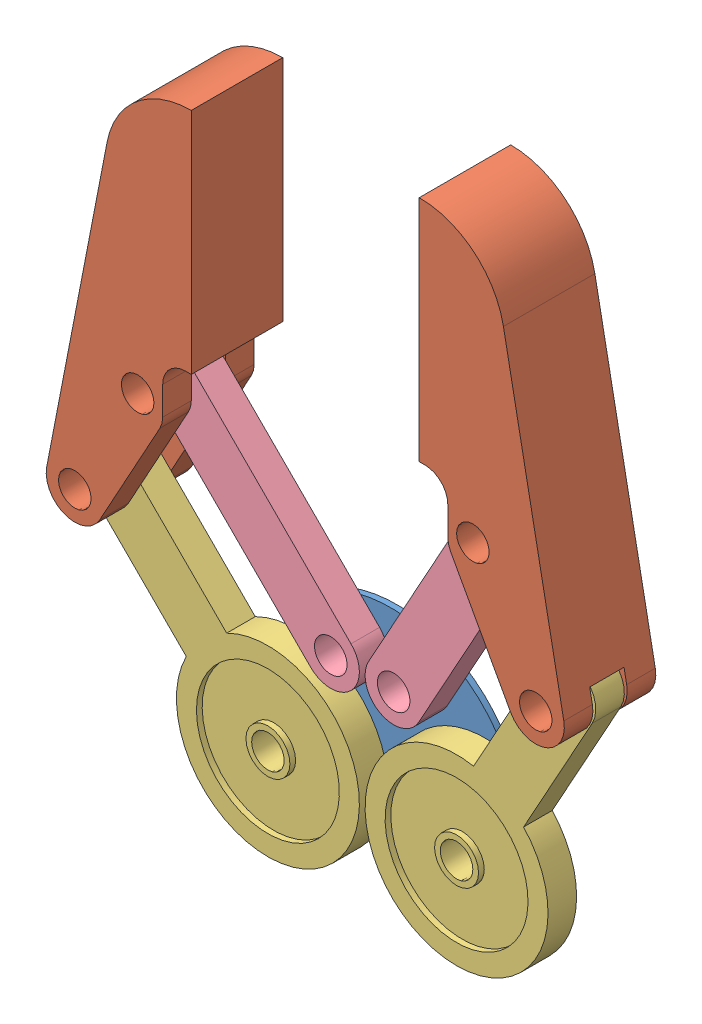
SolidWorks assembly Claw_1, configuration Default. Lengths in mm.
Overall size (111.91 125.22 16).
7 component instances, 4 part files, 18 mates.
Components (placement in the parent):
- Arm_Plate-1: Arm_Plate [Default] at (16.3184 9.8304 30.4902) x (0 -1 0) z (0 0 1) size (32.5 45 1)
- Grip-1: Grip [Default] at (31.79 112.4275 25.9902) x (0 -1 0) z (0 0 1) size (72.59 25.38 16)
- Arm_Gear-1: Arm_Gear [Default] at (-14.3238 23.9725 33.9902) x (0.707107 -0.707107 0) z (0 0 1) size (61 32 5)
- Arm_Link-1: Arm_Link [Default] at (31.4948 47.3338 33.9902) x (-0.483819 -0.875168 0) z (0 0 -1) size (50 10 5)
- Arm_Link-2: Arm_Link [Default] at (-3.3238 43.9725 33.9902) x (0.707107 -0.707107 0) z (0 0 -1) size (50 10 5)
- Arm_Gear-2: Arm_Gear [Default] at (42.4948 27.3338 33.9902) x (-0.483819 -0.875168 0) z (0 0 1) size (61 32 5)
- Grip-2: Grip [Default] at (-8.0848 105.7051 41.9902) x (0 -1 0) z (0 0 -1) size (72.59 25.38 16)
Mates (geometry in assembly coordinates):
- Coincident2: coincident anti-aligned: plane of Arm_Plate-1 through (16.3184 14.8304 31.4902) normal (0 0 1); plane of Arm_Gear-1 through (-4.0627 49.6417 31.4902) normal (0 0 -1)
- Concentric1: concentric aligned: cylinder of Arm_Plate-1 through (-0.1816 9.8304 31.4902) axis (0 0 -1) radius 2.85; cylinder of Arm_Gear-1 through (-0.1816 9.8304 36.4902) axis (0 0 -1) radius 2.85
- Concentric2: concentric aligned: cylinder of Arm_Plate-1 through (32.8184 9.8304 31.4902) axis (0 0 -1) radius 2.85; cylinder of Arm_Gear-2 through (32.8184 9.8304 36.4902) axis (0 0 -1) radius 2.85
- Coincident3: coincident anti-aligned: plane of Arm_Plate-1 through (16.3184 14.8304 31.4902) normal (0 0 1); plane of Arm_Gear-2 through (36.6995 49.6417 31.4902) normal (0 0 -1)
- Concentric3: concentric anti-aligned: cylinder of Arm_Gear-1 through (-4.0627 49.6417 36.4902) axis (0 0 -1) radius 2.85; cylinder of Grip-2 through (-4.0627 49.6417 36.9902) axis (0 0 1) radius 2.85
- Concentric4: concentric aligned: cylinder of Grip-1 through (36.6995 49.6417 41.9902) axis (0 0 -1) radius 2.85; cylinder of Arm_Gear-2 through (36.6995 49.6417 36.4902) axis (0 0 -1) radius 2.85
- Width1: width anti-aligned: plane of Grip-1 through (79.1256 44.6417 36.9902) normal (0 0 -1); plane of Arm_Gear-2 through (17.3184 73.2321 30.9902) normal (0 0 1); plane of Grip-1 through (36.6995 49.6417 36.4902) normal (0 0 1); plane of Arm_Gear-2 through (36.6995 49.6417 31.4902) normal (0 0 -1)
- Width2: width anti-aligned: plane of Grip-2 through (-46.4889 44.6417 30.9902) normal (0 0 1); plane of Arm_Gear-1 through (15.3184 73.2321 36.9902) normal (0 0 -1); plane of Grip-2 through (-4.0627 49.6417 31.4902) normal (0 0 -1); plane of Arm_Gear-1 through (-4.0627 49.6417 36.4902) normal (0 0 1)
- Concentric5: concentric anti-aligned: cylinder of Arm_Plate-1 through (21.8184 29.8304 31.4902) axis (0 0 -1) radius 2.85; cylinder of Arm_Link-1 through (21.8184 29.8304 31.4902) axis (0 0 1) radius 2.85
- Coincident4: coincident anti-aligned: plane of Grip-1 through (32.0426 112.2867 41.9902) normal (-1 0 0); plane of Grip-2 through (-8.0848 105.7051 25.9902) normal (1 0 0)
- Concentric6: concentric anti-aligned: cylinder of Grip-1 through (25.6995 69.6417 41.9902) axis (0 0 -1) radius 2.85; cylinder of Arm_Link-1 through (25.6995 69.6417 31.4902) axis (0 0 1) radius 2.85
- Concentric7: concentric anti-aligned: cylinder of Arm_Plate-1 through (10.8184 29.8304 31.4902) axis (0 0 -1) radius 2.85; cylinder of Arm_Link-2 through (10.8184 29.8304 31.4902) axis (0 0 1) radius 2.85
- Concentric8: concentric aligned: cylinder of Arm_Link-2 through (6.9373 69.6417 31.4902) axis (0 0 1) radius 2.85; cylinder of Grip-2 through (6.9373 69.6417 36.9902) axis (0 0 1) radius 2.85
- Coincident5: coincident anti-aligned: plane of Arm_Plate-1 through (16.3184 14.8304 31.4902) normal (0 0 1); plane of Arm_Link-1 through (25.6995 69.6417 31.4902) normal (0 0 -1)
- Coincident6: coincident anti-aligned: plane of Arm_Plate-1 through (16.3184 14.8304 31.4902) normal (0 0 1); plane of Arm_Link-2 through (6.9373 69.6417 31.4902) normal (0 0 -1)
- Coincident7: coincident anti-aligned: line of Grip-1 through (32.0426 112.2867 41.9902) axis (0 0 -1); line of Grip-2 through (-8.0848 105.7051 25.9902) axis (0 0 1)
- GearMate2: gear = 54 : 32 mm: circle of Arm_Gear-1; circle of Arm_Gear-2
- Angle2: planar angle = 0.785398 rad anti-aligned: plane of Arm_Gear-1 through (-32.0014 34.5791 36.4902) normal (-0.707107 -0.707107 0)
